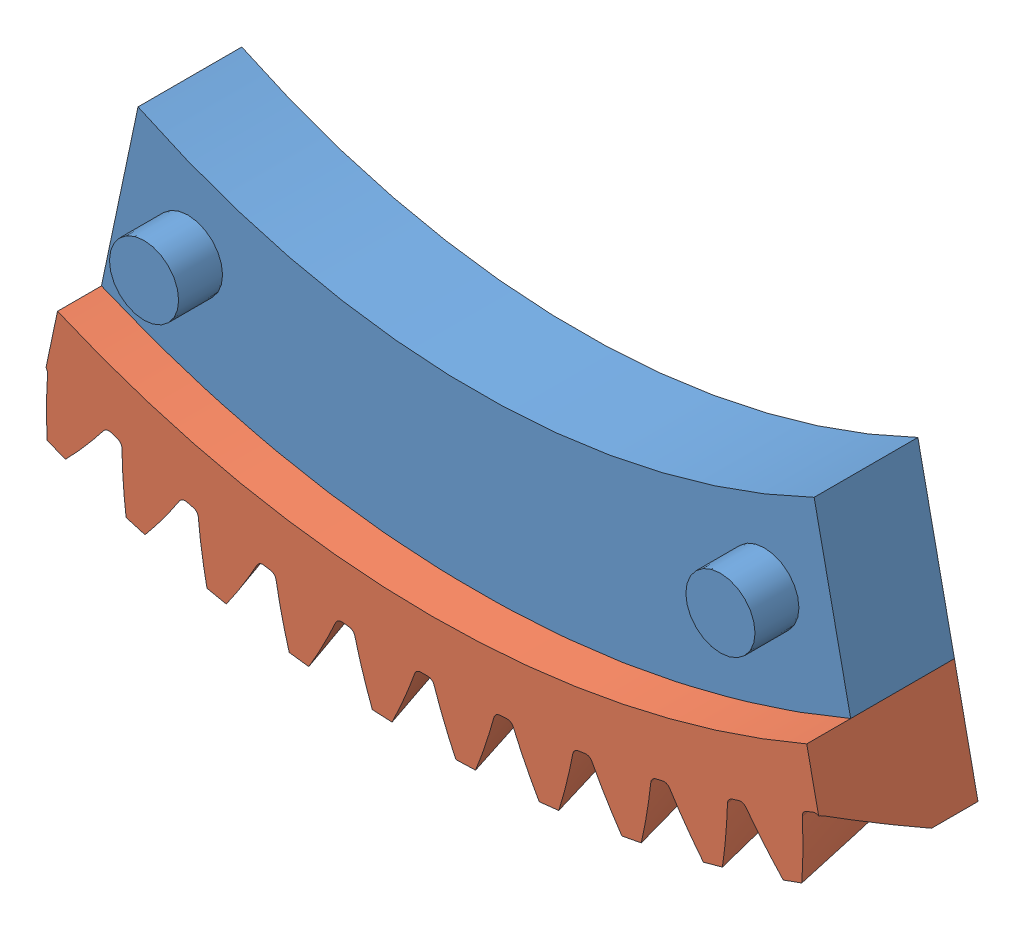
SolidWorks assembly gear_attach, configuration Default. Lengths in mm.
Overall size (48.54 123.02 10).
2 component instances, 2 part files, 2 mates.
Components (placement in the parent):
- 3d_extend-1: 3d_extend [Default] at (19.7747 70.7207 27.1233) size (43.33 14.47 8.54)
- Metric - RH Helical gear 1.5M 80T 0HA 20PA 10mmFW ---80N75H50L110.0N-1: Metric - RH Helical gear 1.5M 80T 0HA 20PA 10mmFW ---80N75H50L110.0N [Metric - RH Helical gear 1.5M 80T 0HA 20PA 10mmFW ---80N75H50L110.0N] at (19.7747 70.7207 37.1233) x (0 0 -1) z (1 0 0) size (10 123.04 123.04)
Mates (geometry in assembly coordinates):
- Concentric1: concentric anti-aligned: cylinder of 3d_extend-1 through (19.7747 70.7207 33.1233) axis (0 0 -1) radius 55; cylinder of Metric - RH Helical gear 1.5M 80T 0HA 20PA 10mmFW ---80N75H50L110.0N-1 through (19.7747 70.7207 -25.3767) axis (0 0 1) radius 55
- Coincident1: coincident aligned: plane of 3d_extend-1 through (19.7747 70.7207 27.1233) normal (0 0 -1); plane of Metric - RH Helical gear 1.5M 80T 0HA 20PA 10mmFW ---80N75H50L110.0N-1 through (19.7747 70.7207 27.1233) normal (0 0 -1)
